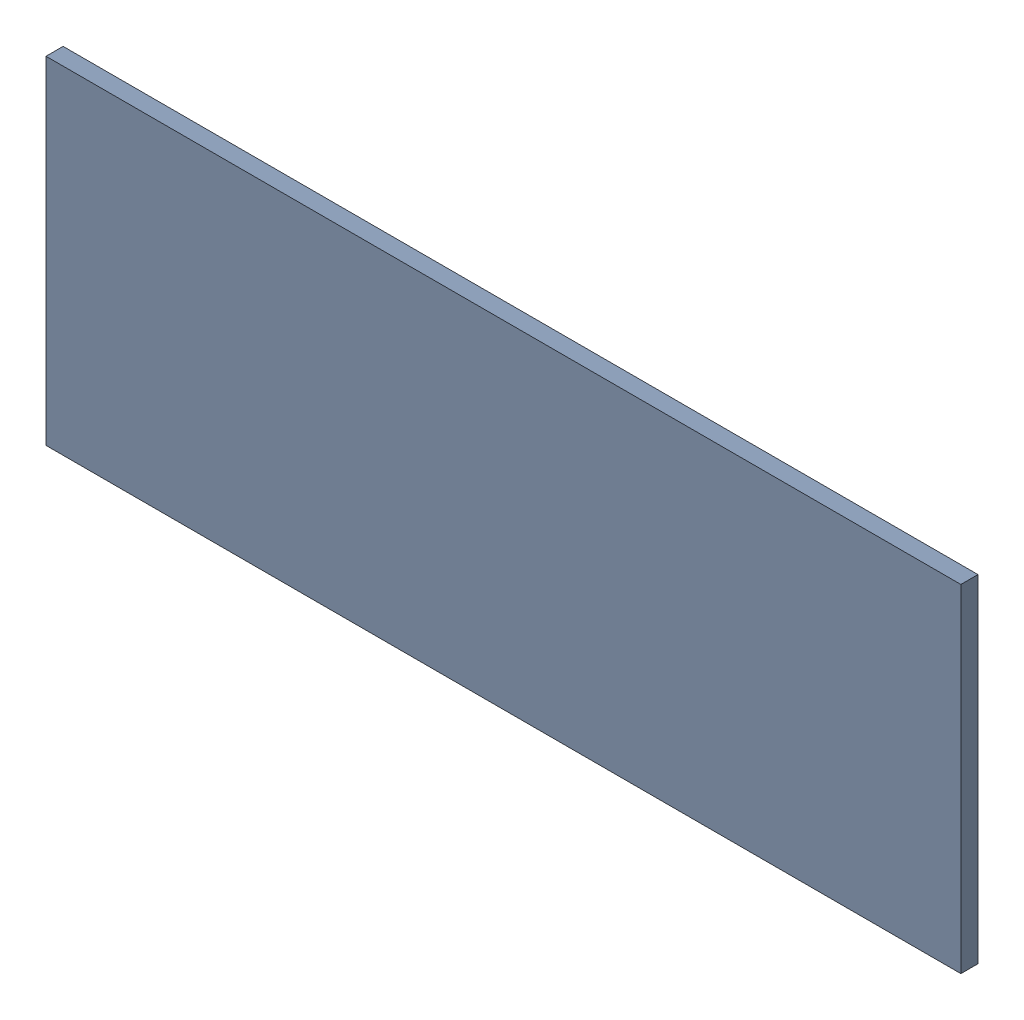
SolidWorks assembly Pad RAK4600-11(14.5mm,15mm) on Top Layer, configuration Predeterminado. Lengths in mm.
Overall size (1.9 0.7 0.04).
2 component instances, 1 part files, 0 mates.
Components (placement in the parent):
- Pad RAK4600-11(14.5mm,15mm) on Top Layer-1-1: Pad RAK4600-11(14.5mm,15mm) on Top Layer-1 [Predeterminado] at (-68.317 -44.187 -0.0457) size (1.9 0.7 0.04)
  - Pad RAK4600-11(14.5mm,15mm) on Top Layer-Part-1-1: Pad RAK4600-11(14.5mm,15mm) on Top Layer-Part-1 [Predeterminado] at origin size (1.9 0.7 0.04)
